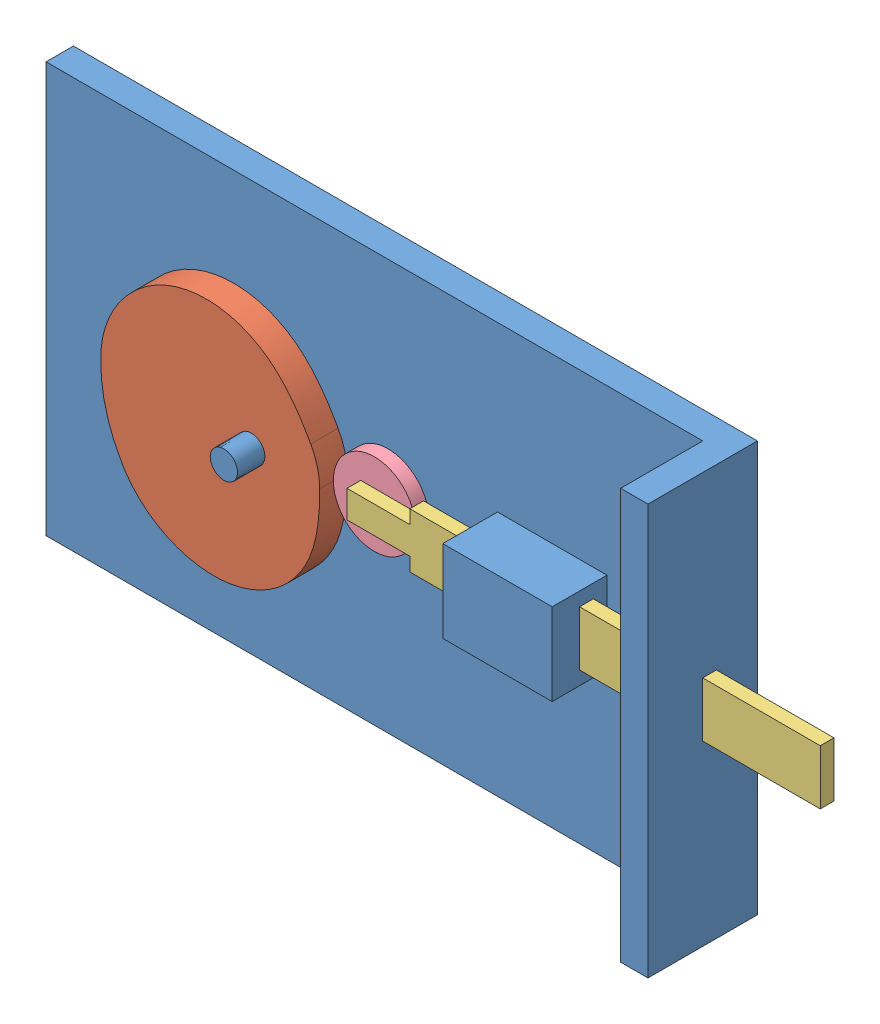
SolidWorks assembly Assem1, configuration Default. Lengths in mm.
Overall size (292.97 150 40).
4 component instances, 4 part files, 6 mates.
Components (placement in the parent):
- base-1: base [Default] at (34.1024 135.7611 219.5448) size (250 150 40)
- Cam-1: Cam [Default] at (-5.8976 135.7611 239.5448) x (0.006109 0.999981 0) z (-0.999981 0.006109 0) size (92.67 10 80.66)
- Connecting Rod-1: Connecting Rod [Default] at (127.0713 135.7611 234.5448) size (172.97 20 10)
- Roller-1: Roller [Default] at (34.1011 135.7611 229.5448) x (0.729199 0.684302 0) z (0 0 1) size (30 30 5)
Mates (geometry in assembly coordinates):
- Coincident1: coincident anti-aligned: plane of base-1 through (34.1024 135.7611 229.5448) normal (0 0 1); plane of Cam-1 through (-6.0493 91.1767 229.5448) normal (0 0 -1)
- Concentric1: concentric anti-aligned: cylinder of base-1 through (-5.8976 135.7611 249.5448) axis (0 0 -1) radius 5; cylinder of Cam-1 through (-5.8976 135.7611 229.5448) axis (0 0 1) radius 5
- Coincident7: coincident anti-aligned: plane of base-1 through (136.6589 145.7611 234.5448) normal (0 0 1); plane of Connecting Rod-1 through (127.0713 135.7611 234.5448) normal (0 0 -1)
- Coincident8: coincident anti-aligned: plane of base-1 through (74.1024 145.7611 249.5448) normal (0 -1 0); plane of Connecting Rod-1 through (52.0713 145.7611 239.5448) normal (0 1 0)
- Concentric2: concentric anti-aligned: cylinder of Connecting Rod-1 through (34.1011 135.7611 229.5448) axis (0 0 1) radius 5; cylinder of Roller-1 through (34.1011 135.7611 234.5448) axis (0 0 -1) radius 5
- Coincident9: coincident anti-aligned: plane of base-1 through (34.1024 135.7611 229.5448) normal (0 0 1); plane of Roller-1 through (34.1011 135.7611 229.5448) normal (0 0 -1)
